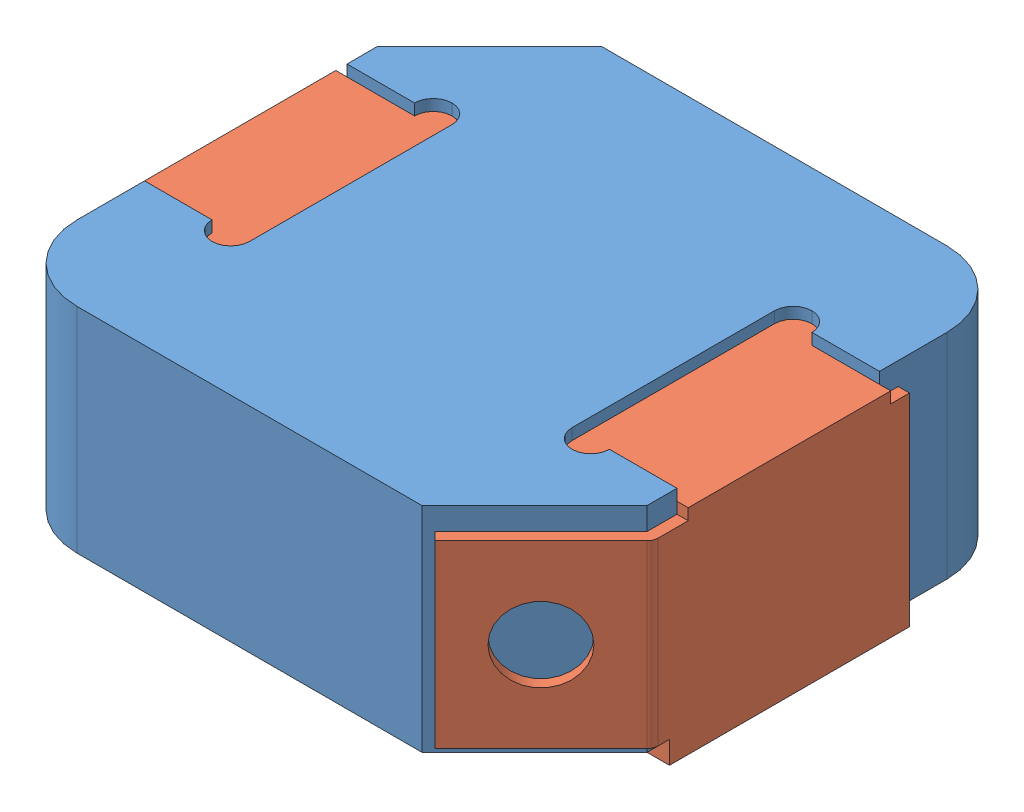
SolidWorks assembly Assem1, configuration Default. Lengths in mm.
Overall size (7.4 3 6.54).
3 component instances, 2 part files, 9 mates.
Components (placement in the parent):
- Body-1: Body [Default] at (0 0.15 0) size (7.1 2.85 6.5)
- Terminal-1: Terminal [Default] at (3.7 0 0) x (-1 0 0) z (0 0 -1) size (1.56 2.85 4.87)
- Terminal-2: Terminal [Default] at (-3.7 0 0) size (1.56 2.85 4.87)
Mates (geometry in assembly coordinates):
- Coincident1: coincident: plane of Body-1 through (0 0.15 0) normal (1 0 0); plane of assembly
- Coincident2: coincident: plane of Body-1 through (0 0.15 0) normal (0 0 1); plane of assembly
- Distance1: distance = 0.15 mm: plane of assembly; plane of Body-1 through (0 0.15 0) normal (0 -1 0)
- Coincident4: coincident: plane of Body-1 through (3.55 3 3.25) normal (1 0 0); plane of Terminal-1 through (3.55 2.7 1.6) normal (-1 0 0)
- Coincident5: coincident: plane of Body-1 through (3.55 3 1.75) normal (0.707107 0 0.707107); plane of Terminal-1 through (3.55 0.3 1.75) normal (-0.707107 0 -0.707107)
- Coincident6: coincident: plane of Body-1 through (0 2.7 0) normal (0 1 0); plane of Terminal-1 through (3.7 2.7 0) normal (0 -1 0)
- Coincident7: coincident: plane of Body-1 through (-3.55 3 3.25) normal (-1 0 0); plane of Terminal-2 through (-3.55 -1.6277 -1.6) normal (1 0 0)
- Coincident8: coincident: plane of Body-1 through (-3.55 3 -1.75) normal (-0.707107 0 -0.707107); plane of Terminal-2 through (-3.55 -4.0277 -1.75) normal (0.707107 0 0.707107)
- Coincident9: coincident: plane of Body-1 through (0 2.7 0) normal (0 1 0); plane of Terminal-2 through (-3.7 2.7 0) normal (0 -1 0)
